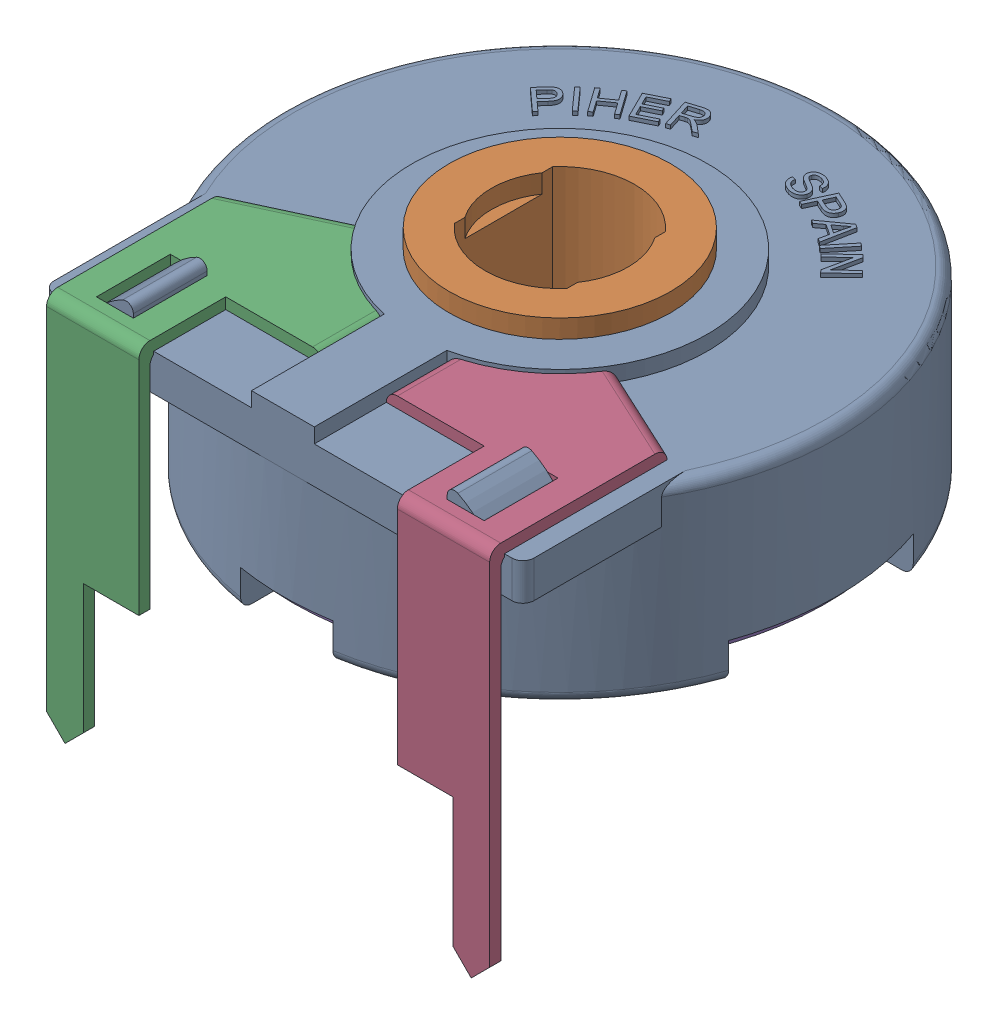
SolidWorks assembly Trimmer_Piher_PT-15(2), configuration Default. Lengths in mm.
Overall size (15 10.9 15.4).
3 component instances, 3 part files, 0 mates.
Components (placement in the parent):
- Corps_PT-15-1: Corps_PT-15 [Default] at (-10.6222 0.2667 0) size (15 5.61 15)
- Axe-1: Axe [Default] at (-10.6222 5.6667 0) x (-1 0 0) z (0 1 0) size (7.5 7.5 5.7)
- Broche 1-1: Broche 1 [Default] at (-10.6222 5.2667 0) x (-1 0 0) z (0 1 0) size (14.44 15.12 10.3)
